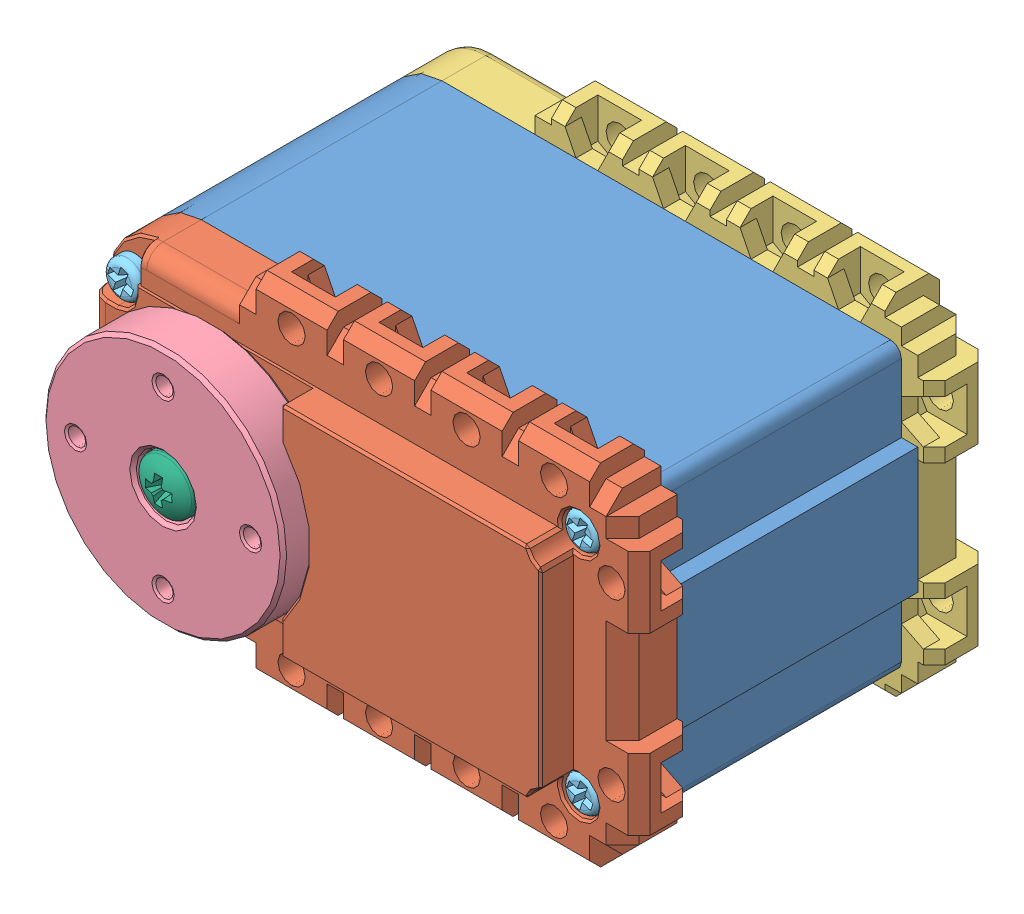
SolidWorks assembly AX-12A, configuration Default. Lengths in mm.
Overall size (50 32 40.55).
9 component instances, 6 part files, 14 mates.
Components (placement in the parent):
- AX-12A-01-1: AX-12A-01 [Default] at origin size (48.5 26 22)
- AX-12A-02-1: AX-12A-02 [Default] at (0 0 13.5) size (50 32 8)
- AX-12A-03-1: AX-12A-03 [Default] at (0 0 -13.5) x (1 0 0) z (0 0 -1) size (50 32 8)
- AX-12A-04-1: AX-12A-04 [Default] at (0 0 21) size (22 22 6.7)
- SetScrew-5: SetScrew [Default] at (33 10.4 14.5) x (0.31498 0.949098 0) z (0 0 -1) size (3.3 3.3 29.44)
- SetScrew-6: SetScrew [Default] at (-9 9.25 14.5) x (0.31498 0.949098 0) z (0 0 -1) size (3.3 3.3 29.44)
- SetScrew-7: SetScrew [Default] at (-9 -9.25 14.5) x (-0.958559 0.284893 0) z (0 0 -1) size (3.3 3.3 29.44)
- SetScrew-8: SetScrew [Default] at (33 -10.4 14.5) x (0.31498 0.949098 0) z (0 0 -1) size (3.3 3.3 29.44)
- pan head cross recess screw_iso-1: pan head cross recess screw_iso [ISO 7045 - M2.5 x 8 - Z --- 8C] at (0 0 21.6) x (0 0 -1) z (1 0 0) size (10.05 5 5)
Mates (geometry in assembly coordinates):
- Coincident1: coincident anti-aligned: plane of AX-12A-01-1 through (0 0 11) normal (0 0 1); plane of AX-12A-02-1 through (0 0 11) normal (0 0 -1)
- Coincident2: coincident aligned: plane of AX-12A-01-1 through (0 0 0) normal (1 0 0); plane of AX-12A-02-1 through (0 0 13.5) normal (1 0 0)
- Coincident3: coincident aligned: plane of AX-12A-01-1 through (0 0 0) normal (0 1 0); plane of AX-12A-02-1 through (0 0 13.5) normal (0 1 0)
- Coincident4: coincident anti-aligned: plane of AX-12A-01-1 through (0 0 -11) normal (0 0 -1); plane of AX-12A-03-1 through (0 0 -11) normal (0 0 1)
- Coincident5: coincident aligned: plane of AX-12A-01-1 through (0 0 0) normal (1 0 0); plane of AX-12A-03-1
- Coincident6: coincident anti-aligned: plane of AX-12A-01-1 through (0 0 0) normal (0 1 0); plane of AX-12A-03-1 through (0 0 -13.5) normal (0 -1 0)
- Concentric2: concentric aligned: cylinder of AX-12A-02-1 through (33 10.4 11) axis (0 0 1) radius 1; cylinder of SetScrew-5 through (33 10.4 14.5) axis (0 0 1) radius 0.85
- Coincident8: coincident anti-aligned: plane of AX-12A-02-1 through (0 0 14.5) normal (0 0 1); plane of SetScrew-5 through (33.8067 10.1323 14.5) normal (0 0 -1)
- Concentric3: concentric aligned: cylinder of AX-12A-02-1 through (-9 9.25 11) axis (0 0 1) radius 1; cylinder of SetScrew-6 through (-9 9.25 14.5) axis (0 0 1) radius 0.85
- Coincident9: coincident anti-aligned: plane of AX-12A-02-1 through (0 0 14.5) normal (0 0 1); plane of SetScrew-6 through (-8.1933 8.9823 14.5) normal (0 0 -1)
- Concentric4: concentric aligned: cylinder of AX-12A-02-1 through (-9 -9.25 11) axis (0 0 1) radius 1; cylinder of SetScrew-7 through (-9 -9.25 14.5) axis (0 0 1) radius 0.85
- Coincident10: coincident anti-aligned: plane of AX-12A-02-1 through (0 0 14.5) normal (0 0 1); plane of SetScrew-7 through (-8.7578 -8.4352 14.5) normal (0 0 -1)
- Concentric5: concentric aligned: cylinder of AX-12A-02-1 through (33 -10.4 11) axis (0 0 1) radius 1; cylinder of SetScrew-8 through (33 -10.4 14.5) axis (0 0 1) radius 0.85
- Coincident11: coincident anti-aligned: plane of AX-12A-02-1 through (0 0 14.5) normal (0 0 1); plane of SetScrew-8 through (33.8067 -10.6677 14.5) normal (0 0 -1)
